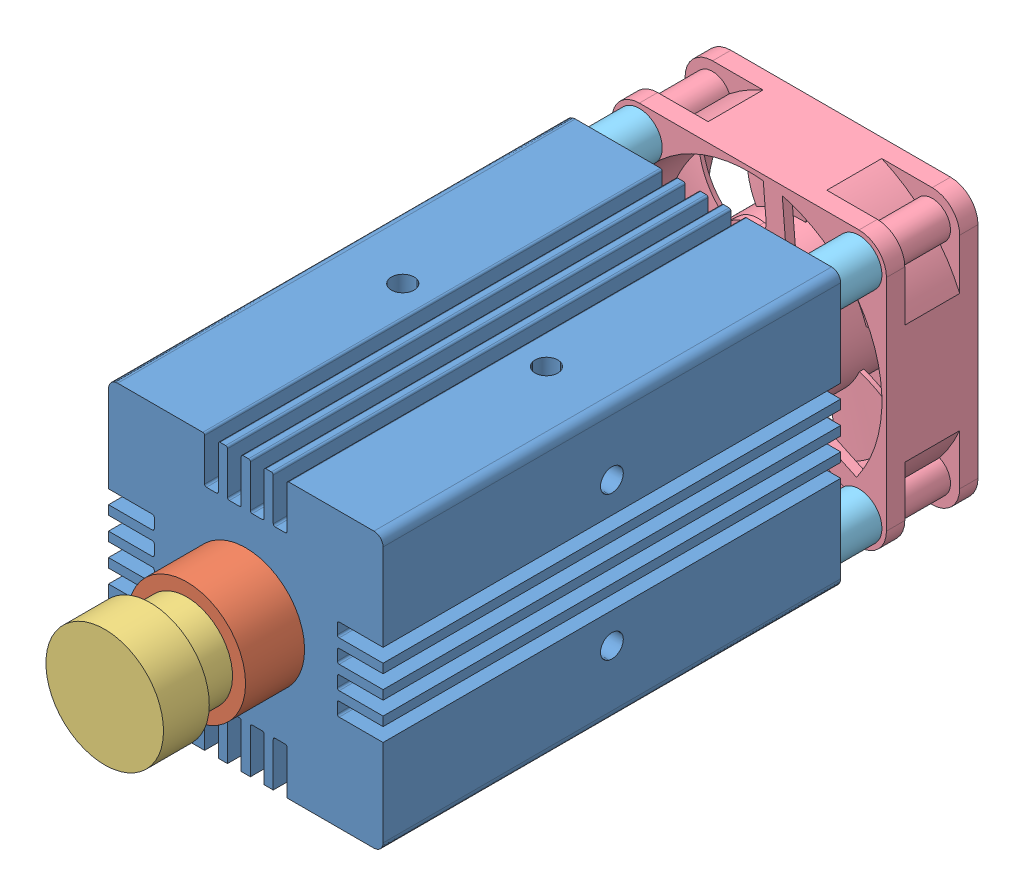
SolidWorks assembly diode, configuration Default. Lengths in mm.
Overall size (31.36 31.11 80.41).
9 component instances, 6 part files, 13 mates.
Components (placement in the parent):
- Heatsink-1: Heatsink [Default] at origin size (30 30 50)
- Part2-1: Part2 [Default] at origin
- Diode-1: Diode [Default] at (0 0 50) size (12.85 12.85 20.98)
- Lens-1: Lens [Default] at (-4.0368 5.6405 54.414) x (0.946543 -0.322578 0) z (0 0 1) size (12.85 12.85 11)
- FAN for Heat Sink (Hotend)-1: FAN for Heat Sink (Hotend) [Default] at (15 15 -10) size (31.36 31.11 10)
- Part2^diode-1: Part2^diode [Default] at (-3.1611 3.584 0) x (-0.992168 0.124909 0) z (0 0 -1) size (5 5 5) (virtual)
- Part2^diode-2: Part2^diode [Default] at (54 -24 -5) size (5 5 5) (virtual)
- Part2^diode-3: Part2^diode [Default] at (30 -24 -5) size (5 5 5) (virtual)
- Part2^diode-4: Part2^diode [Default] at (25.6016 -3.7761 -5) x (0.988476 -0.151379 0) z (0 0 1) size (5 5 5) (virtual)
Mates (geometry in assembly coordinates):
- Coincident1: coincident aligned: plane of Heatsink-1 through (30 0 50) normal (1 0 0); plane of FAN for Heat Sink (Hotend)-1 through (30 8.515 -7) normal (1 0 0)
- Coincident2: coincident aligned: plane of Heatsink-1 through (0 30 50) normal (0 1 0); plane of FAN for Heat Sink (Hotend)-1 through (21.485 30 -7) normal (0 1 0)
- Concentric1: concentric aligned: cylinder of FAN for Heat Sink (Hotend)-1 through (3 27 -15) axis (0 0 1) radius 1.6; cylinder of Part2^diode-4 through (3 27 0) axis (0 0 1) radius 1.8
- Coincident3: coincident anti-aligned: plane of Heatsink-1 through (0 0 0) normal (0 0 -1); plane of Part2^diode-4 through (3 27 0) normal (0 0 1)
- Concentric2: concentric anti-aligned: cylinder of FAN for Heat Sink (Hotend)-1 through (27 27 -15) axis (0 0 1) radius 1.6; cylinder of Part2^diode-1 through (27 27 -5) axis (0 0 -1) radius 1.8
- Coincident4: coincident anti-aligned: plane of Heatsink-1 through (0 0 0) normal (0 0 -1); plane of Part2^diode-1 through (27 27 0) normal (0 0 1)
- Coincident5: coincident anti-aligned: plane of Heatsink-1 through (0 0 0) normal (0 0 -1); plane of Part2^diode-2 through (27 3 0) normal (0 0 1)
- Concentric3: concentric aligned: cylinder of FAN for Heat Sink (Hotend)-1 through (27 3 -15) axis (0 0 1) radius 1.6; cylinder of Part2^diode-2 through (27 3 0) axis (0 0 1) radius 1.8
- Concentric4: concentric aligned: cylinder of FAN for Heat Sink (Hotend)-1 through (3 3 -15) axis (0 0 1) radius 1.6; cylinder of Part2^diode-3 through (3 3 0) axis (0 0 1) radius 1.8
- Coincident6: coincident anti-aligned: plane of Heatsink-1 through (0 0 0) normal (0 0 -1); plane of Part2^diode-3 through (3 3 0) normal (0 0 1)
- Concentric5: concentric anti-aligned: cylinder of Diode-1 through (15 15 35.4729) axis (0 0 1) radius 6.425; cylinder of Lens-1 through (15 15 65.414) axis (0 0 -1) radius 6.425
- Distance1: distance = 6.45 mm aligned: plane of Diode-1 through (15 15 56.45) normal (0 0 1); plane of Heatsink-1 through (0 0 50) normal (0 0 1)
- Distance2: distance = 3.964 mm anti-aligned: plane of Lens-1 through (15 15 60.414) normal (0 0 -1); plane of Diode-1 through (15 15 56.45) normal (0 0 1)
